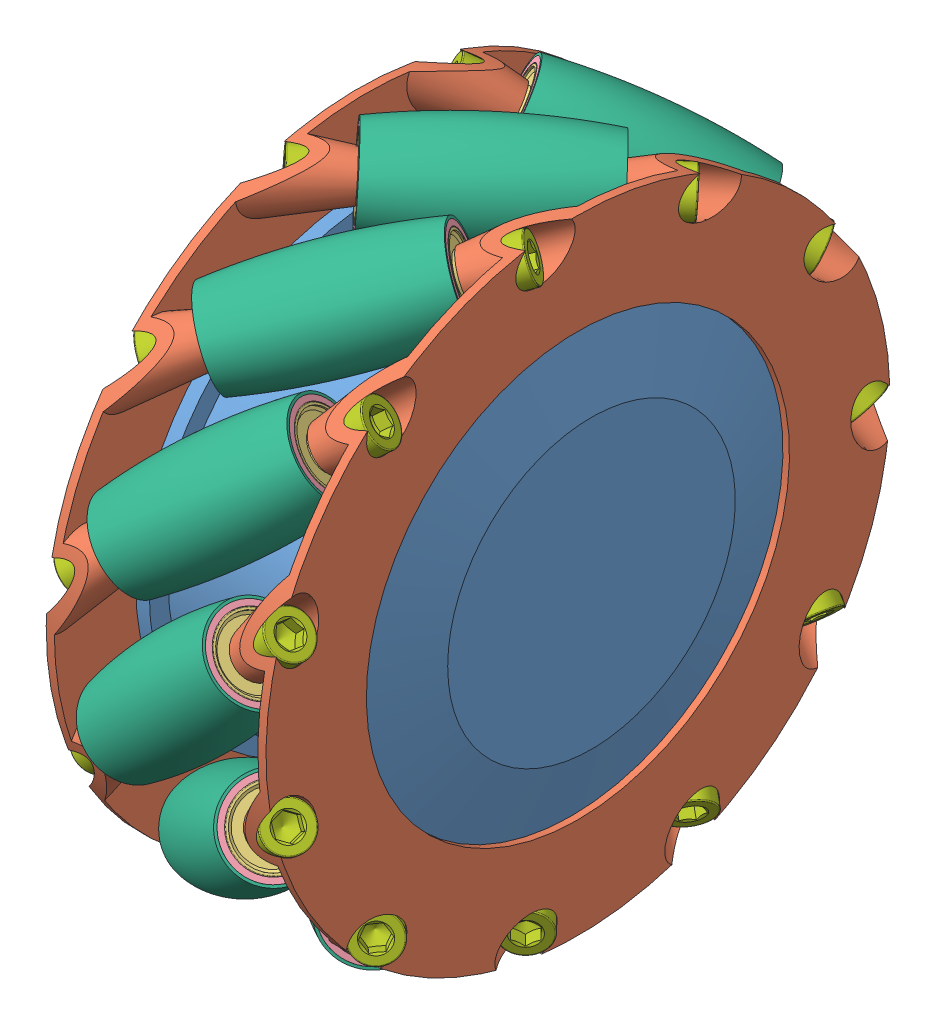
SolidWorks assembly ТП.SH21(К4).01.00 - Колесо Б, configuration 00. Lengths in mm.
Overall size (149.42 275.46 275.46).
102 component instances, 8 part files, 10 mates.
Components (placement in the parent):
- Мотор-колесо ZLLG80ASM800 (мотор)-1: Мотор-колесо ZLLG80ASM800 (мотор) [1 крепление] at origin size (133 170 170)
- ТП.SH21(К4).01.01 - Фланец колеса-1: ТП.SH21(К4).01.01 - Фланец колеса [11] at (-43.5 0 0) x (0 -0.998143 -0.060917) z (-1 0 0) size (230 230 42.83)
- ТП.SH21(К4).01.02.00 - Ролик диагональный-1: ТП.SH21(К4).01.02.00 - Ролик диагональный [00] at (0 101.1602 -8.298) x (0.7067 0.023978 0.707107) z (-0.707107 0.057808 0.70474) size (37 37 69.98)
  - Боченок габарит-1: Боченок габарит [--] at origin size (37 37 91.92) (hidden)
  - Подшипник 6100-1: Подшипник 6100 [--] at (0 0 30.99) x (0 0 1) z (0.161819 -0.986821 0) size (8 26 26)
  - ТП.SH21(К4).01.02.01 - Ступица-1: ТП.SH21(К4).01.02.01 - Ступица [--] at origin size (30 30 69.98)
  - ТП.SH21(К4).01.02.02 - Ось-1: ТП.SH21(К4).01.02.02 - Ось [--] at origin size (14 14 53.98)
  - Подшипник 6100-2: Подшипник 6100 [--] at (0 0 -30.99) x (0 0 -1) z (-0.273874 0.961766 0) size (8 26 26)
  - ТП.SH21(К4).01.02.03 - Покрышка-1: ТП.SH21(К4).01.02.03 - Покрышка [--] at origin size (37 37 69.98)
- ТП.SH21(К4).01.01 - Фланец колеса-2: ТП.SH21(К4).01.01 - Фланец колеса [11] at (43.5 0 0) x (0 -0.974873 0.22276) z (1 0 0) size (230 230 42.83)
- Винты с цилиндрической головкой (ГОСТ 11738-84)-1: Винты с цилиндрической головкой (ГОСТ 11738-84) [Винт М10-(6g)x35 ГОСТ 11738-84] at (-31.1056 103.7032 22.7036) x (0.312231 0.919754 0.237834) z (-0.707107 0.057808 0.70474) size (16 16 45.28)
- Винты с цилиндрической головкой (ГОСТ 11738-84)-2: Винты с цилиндрической головкой (ГОСТ 11738-84) [Винт М10-(6g)x35 ГОСТ 11738-84] at (31.1056 98.6173 -39.2995) x (0.69696 0.225211 0.680828) z (0.707107 -0.057808 -0.70474) size (16 16 45.28)
- Винты с цилиндрической головкой (ГОСТ 11738-84)-4: Винты с цилиндрической головкой (ГОСТ 11738-84) [Винт М10-(6g)x35 ГОСТ 11738-84] at (-31.1056 99.5152 -36.9667) x (0.312231 0.902329 -0.297178) z (-0.707107 0.429643 0.561611) size (16 16 45.28)
- Винты с цилиндрической головкой (ГОСТ 11738-84)-5: Винты с цилиндрической головкой (ГОСТ 11738-84) [Винт М10-(6g)x35 ГОСТ 11738-84] at (-31.1056 63.7318 -84.9004) x (0.312231 0.598421 -0.737838) z (-0.707107 0.665068 0.240175) size (16 16 45.28)
- Винты с цилиндрической головкой (ГОСТ 11738-84)-6: Винты с цилиндрической головкой (ГОСТ 11738-84) [Винт М10-(6g)x35 ГОСТ 11738-84] at (-31.1056 7.714 -105.8787) x (0.312231 0.104518 -0.944239) z (-0.707107 0.68934 -0.157515) size (16 16 45.28)
- Винты с цилиндрической головкой (ГОСТ 11738-84)-7: Винты с цилиндрической головкой (ГОСТ 11738-84) [Винт М10-(6g)x35 ГОСТ 11738-84] at (-31.1056 -50.753 -93.2413) x (0.312231 -0.422568 -0.850852) z (-0.707107 0.49475 -0.505195) size (16 16 45.28)
- Винты с цилиндрической головкой (ГОСТ 11738-84)-8: Винты с цилиндрической головкой (ГОСТ 11738-84) [Винт М10-(6g)x35 ГОСТ 11738-84] at (-31.1056 -93.1062 -51.0005) x (0.312231 -0.815492 -0.487325) z (-0.707107 0.143082 -0.692479) size (16 16 45.28)
- Винты с цилиндрической головкой (ГОСТ 11738-84)-9: Винты с цилиндрической головкой (ГОСТ 11738-84) [Винт М10-(6g)x35 ГОСТ 11738-84] at (-31.1056 -105.8988 7.4327) x (0.312231 -0.949503 0.030925) z (-0.707107 -0.254015 -0.659906) size (16 16 45.28)
- Винты с цилиндрической головкой (ГОСТ 11738-84)-10: Винты с цилиндрической головкой (ГОСТ 11738-84) [Винт М10-(6g)x35 ГОСТ 11738-84] at (-31.1056 -85.0694 63.506) x (0.312231 -0.782054 0.539356) z (-0.707107 -0.570463 -0.417818) size (16 16 45.28)
- Винты с цилиндрической головкой (ГОСТ 11738-84)-11: Винты с цилиндрической головкой (ГОСТ 11738-84) [Винт М10-(6g)x35 ГОСТ 11738-84] at (-31.1056 -37.231 99.4166) x (0.312231 -0.366308 0.876545) z (-0.707107 -0.705794 -0.043075) size (16 16 45.28)
- Винты с цилиндрической головкой (ГОСТ 11738-84)-12: Винты с цилиндрической головкой (ГОСТ 11738-84) [Винт М10-(6g)x35 ГОСТ 11738-84] at (-31.1056 22.428 103.7632) x (0.312231 0.165738 0.935437) z (-0.707107 -0.617039 0.345344) size (16 16 45.28)
- Винты с цилиндрической головкой (ГОСТ 11738-84)-13: Винты с цилиндрической головкой (ГОСТ 11738-84) [Винт М10-(6g)x35 ГОСТ 11738-84] at (-31.1056 74.9662 75.1656) x (0.312231 0.645163 0.697335) z (-0.707107 -0.33238 0.624118) size (16 16 45.28)
- ТП.SH21(К4).01.02.00 - Ролик диагональный-2: ТП.SH21(К4).01.02.00 - Ролик диагональный [00] at (0 80.6152 -61.672) x (0.7067 0.402463 0.581892) z (-0.707107 0.429643 0.561611) size (37 37 69.98)
  - Боченок габарит-1: Боченок габарит [--] at origin size (37 37 91.92) (hidden)
  - Подшипник 6100-1: Подшипник 6100 [--] at (0 0 30.99) x (0 0 1) z (0.161819 -0.986821 0) size (8 26 26)
  - ТП.SH21(К4).01.02.01 - Ступица-1: ТП.SH21(К4).01.02.01 - Ступица [--] at origin size (30 30 69.98)
  - ТП.SH21(К4).01.02.02 - Ось-1: ТП.SH21(К4).01.02.02 - Ось [--] at origin size (14 14 53.98)
  - Подшипник 6100-2: Подшипник 6100 [--] at (0 0 -30.99) x (0 0 -1) z (-0.273874 0.961766 0) size (8 26 26)
  - ТП.SH21(К4).01.02.03 - Покрышка-1: ТП.SH21(К4).01.02.03 - Покрышка [--] at origin size (37 37 69.98)
- ТП.SH21(К4).01.02.00 - Ролик диагональный-3: ТП.SH21(К4).01.02.00 - Ролик диагональный [00] at (0 34.4754 -95.4657) x (0.7067 0.653168 0.271931) z (-0.707107 0.665068 0.240175) size (37 37 69.98)
  - Боченок габарит-1: Боченок габарит [--] at origin size (37 37 91.92) (hidden)
  - Подшипник 6100-1: Подшипник 6100 [--] at (0 0 30.99) x (0 0 1) z (0.161819 -0.986821 0) size (8 26 26)
  - ТП.SH21(К4).01.02.01 - Ступица-1: ТП.SH21(К4).01.02.01 - Ступица [--] at origin size (30 30 69.98)
  - ТП.SH21(К4).01.02.02 - Ось-1: ТП.SH21(К4).01.02.02 - Ось [--] at origin size (14 14 53.98)
  - Подшипник 6100-2: Подшипник 6100 [--] at (0 0 -30.99) x (0 0 -1) z (-0.273874 0.961766 0) size (8 26 26)
  - ТП.SH21(К4).01.02.03 - Покрышка-1: ТП.SH21(К4).01.02.03 - Покрышка [--] at origin size (37 37 69.98)
- ТП.SH21(К4).01.02.00 - Ролик диагональный-4: ТП.SH21(К4).01.02.00 - Ролик диагональный [00] at (0 -22.6101 -98.9497) x (0.7067 0.696497 -0.124366) z (-0.707107 0.68934 -0.157515) size (37 37 69.98)
  - Боченок габарит-1: Боченок габарит [--] at origin size (37 37 91.92) (hidden)
  - Подшипник 6100-1: Подшипник 6100 [--] at (0 0 30.99) x (0 0 1) z (0.161819 -0.986821 0) size (8 26 26)
  - ТП.SH21(К4).01.02.01 - Ступица-1: ТП.SH21(К4).01.02.01 - Ступица [--] at origin size (30 30 69.98)
  - ТП.SH21(К4).01.02.02 - Ось-1: ТП.SH21(К4).01.02.02 - Ось [--] at origin size (14 14 53.98)
  - Подшипник 6100-2: Подшипник 6100 [--] at (0 0 -30.99) x (0 0 -1) z (-0.273874 0.961766 0) size (8 26 26)
  - ТП.SH21(К4).01.02.03 - Покрышка-1: ТП.SH21(К4).01.02.03 - Покрышка [--] at origin size (37 37 69.98)
- ТП.SH21(К4).01.02.00 - Ролик диагональный-5: ТП.SH21(К4).01.02.00 - Ролик диагональный [00] at (0 -72.517 -71.0178) x (0.7067 0.518693 -0.481178) z (-0.707107 0.49475 -0.505195) size (37 37 69.98)
  - Боченок габарит-1: Боченок габарит [--] at origin size (37 37 91.92) (hidden)
  - Подшипник 6100-1: Подшипник 6100 [--] at (0 0 30.99) x (0 0 1) z (0.161819 -0.986821 0) size (8 26 26)
  - ТП.SH21(К4).01.02.01 - Ступица-1: ТП.SH21(К4).01.02.01 - Ступица [--] at origin size (30 30 69.98)
  - ТП.SH21(К4).01.02.02 - Ось-1: ТП.SH21(К4).01.02.02 - Ось [--] at origin size (14 14 53.98)
  - Подшипник 6100-2: Подшипник 6100 [--] at (0 0 -30.99) x (0 0 -1) z (-0.273874 0.961766 0) size (8 26 26)
  - ТП.SH21(К4).01.02.03 - Покрышка-1: ТП.SH21(К4).01.02.03 - Покрышка [--] at origin size (37 37 69.98)
- ТП.SH21(К4).01.02.00 - Ролик диагональный-6: ТП.SH21(К4).01.02.00 - Ролик диагональный [00] at (0 -99.4003 -20.5383) x (0.7067 0.176208 -0.685219) z (-0.707107 0.143082 -0.692479) size (37 37 69.98)
  - Боченок габарит-1: Боченок габарит [--] at origin size (37 37 91.92) (hidden)
  - Подшипник 6100-1: Подшипник 6100 [--] at (0 0 30.99) x (0 0 1) z (0.161819 -0.986821 0) size (8 26 26)
  - ТП.SH21(К4).01.02.01 - Ступица-1: ТП.SH21(К4).01.02.01 - Ступица [--] at origin size (30 30 69.98)
  - ТП.SH21(К4).01.02.02 - Ось-1: ТП.SH21(К4).01.02.02 - Ось [--] at origin size (14 14 53.98)
  - Подшипник 6100-2: Подшипник 6100 [--] at (0 0 -30.99) x (0 0 -1) z (-0.273874 0.961766 0) size (8 26 26)
  - ТП.SH21(К4).01.02.03 - Покрышка-1: ТП.SH21(К4).01.02.03 - Покрышка [--] at origin size (37 37 69.98)
- ТП.SH21(К4).01.02.00 - Ролик диагональный-7: ТП.SH21(К4).01.02.00 - Ролик диагональный [00] at (0 -94.7247 36.462) x (0.7067 -0.222222 -0.671709) z (-0.707107 -0.254015 -0.659906) size (37 37 69.98)
  - Боченок габарит-1: Боченок габарит [--] at origin size (37 37 91.92) (hidden)
  - Подшипник 6100-1: Подшипник 6100 [--] at (0 0 30.99) x (0 0 1) z (0.161819 -0.986821 0) size (8 26 26)
  - ТП.SH21(К4).01.02.01 - Ступица-1: ТП.SH21(К4).01.02.01 - Ступица [--] at origin size (30 30 69.98)
  - ТП.SH21(К4).01.02.02 - Ось-1: ТП.SH21(К4).01.02.02 - Ось [--] at origin size (14 14 53.98)
  - Подшипник 6100-2: Подшипник 6100 [--] at (0 0 -30.99) x (0 0 -1) z (-0.273874 0.961766 0) size (8 26 26)
  - ТП.SH21(К4).01.02.03 - Покрышка-1: ТП.SH21(К4).01.02.03 - Покрышка [--] at origin size (37 37 69.98)
- ТП.SH21(К4).01.02.00 - Ролик диагональный-8: ТП.SH21(К4).01.02.00 - Ролик диагональный [00] at (0 -59.9747 81.8858) x (0.7067 -0.550098 -0.444935) z (-0.707107 -0.570463 -0.417818) size (37 37 69.98)
  - Боченок габарит-1: Боченок габарит [--] at origin size (37 37 91.92) (hidden)
  - Подшипник 6100-1: Подшипник 6100 [--] at (0 0 30.99) x (0 0 1) z (0.161819 -0.986821 0) size (8 26 26)
  - ТП.SH21(К4).01.02.01 - Ступица-1: ТП.SH21(К4).01.02.01 - Ступица [--] at origin size (30 30 69.98)
  - ТП.SH21(К4).01.02.02 - Ось-1: ТП.SH21(К4).01.02.02 - Ось [--] at origin size (14 14 53.98)
  - Подшипник 6100-2: Подшипник 6100 [--] at (0 0 -30.99) x (0 0 -1) z (-0.273874 0.961766 0) size (8 26 26)
  - ТП.SH21(К4).01.02.03 - Покрышка-1: ТП.SH21(К4).01.02.03 - Покрышка [--] at origin size (37 37 69.98)
- ТП.SH21(К4).01.02.00 - Ролик диагональный-9: ТП.SH21(К4).01.02.00 - Ролик диагональный [00] at (0 -6.1831 101.3115) x (0.7067 -0.703322 -0.076898) z (-0.707107 -0.705794 -0.043075) size (37 37 69.98)
  - Боченок габарит-1: Боченок габарит [--] at origin size (37 37 91.92) (hidden)
  - Подшипник 6100-1: Подшипник 6100 [--] at (0 0 30.99) x (0 0 1) z (0.161819 -0.986821 0) size (8 26 26)
  - ТП.SH21(К4).01.02.01 - Ступица-1: ТП.SH21(К4).01.02.01 - Ступица [--] at origin size (30 30 69.98)
  - ТП.SH21(К4).01.02.02 - Ось-1: ТП.SH21(К4).01.02.02 - Ось [--] at origin size (14 14 53.98)
  - Подшипник 6100-2: Подшипник 6100 [--] at (0 0 -30.99) x (0 0 -1) z (-0.273874 0.961766 0) size (8 26 26)
  - ТП.SH21(К4).01.02.03 - Покрышка-1: ТП.SH21(К4).01.02.03 - Покрышка [--] at origin size (37 37 69.98)
- ТП.SH21(К4).01.02.00 - Ролик диагональный-10: ТП.SH21(К4).01.02.00 - Ролик диагональный [00] at (0 49.5716 88.5715) x (0.7067 -0.633246 0.315554) z (-0.707107 -0.617039 0.345344) size (37 37 69.98)
  - Боченок габарит-1: Боченок габарит [--] at origin size (37 37 91.92) (hidden)
  - Подшипник 6100-1: Подшипник 6100 [--] at (0 0 30.99) x (0 0 1) z (0.161819 -0.986821 0) size (8 26 26)
  - ТП.SH21(К4).01.02.01 - Ступица-1: ТП.SH21(К4).01.02.01 - Ступица [--] at origin size (30 30 69.98)
  - ТП.SH21(К4).01.02.02 - Ось-1: ТП.SH21(К4).01.02.02 - Ось [--] at origin size (14 14 53.98)
  - Подшипник 6100-2: Подшипник 6100 [--] at (0 0 -30.99) x (0 0 -1) z (-0.273874 0.961766 0) size (8 26 26)
  - ТП.SH21(К4).01.02.03 - Покрышка-1: ТП.SH21(К4).01.02.03 - Покрышка [--] at origin size (37 37 69.98)
- ТП.SH21(К4).01.02.00 - Ролик диагональный-11: ТП.SH21(К4).01.02.00 - Ролик диагональный [00] at (0 89.5876 47.7107) x (0.7067 -0.362119 0.60782) z (-0.707107 -0.33238 0.624118) size (37 37 69.98)
  - Боченок габарит-1: Боченок габарит [--] at origin size (37 37 91.92) (hidden)
  - Подшипник 6100-1: Подшипник 6100 [--] at (0 0 30.99) x (0 0 1) z (0.161819 -0.986821 0) size (8 26 26)
  - ТП.SH21(К4).01.02.01 - Ступица-1: ТП.SH21(К4).01.02.01 - Ступица [--] at origin size (30 30 69.98)
  - ТП.SH21(К4).01.02.02 - Ось-1: ТП.SH21(К4).01.02.02 - Ось [--] at origin size (14 14 53.98)
  - Подшипник 6100-2: Подшипник 6100 [--] at (0 0 -30.99) x (0 0 -1) z (-0.273874 0.961766 0) size (8 26 26)
  - ТП.SH21(К4).01.02.03 - Покрышка-1: ТП.SH21(К4).01.02.03 - Покрышка [--] at origin size (37 37 69.98)
- Винты с цилиндрической головкой (ГОСТ 11738-84)-14: Винты с цилиндрической головкой (ГОСТ 11738-84) [Винт М10-(6g)x35 ГОСТ 11738-84] at (31.1056 61.7152 -86.3773) x (0.69696 0.557543 0.45099) z (0.707107 -0.429643 -0.561611) size (16 16 45.28)
- Винты с цилиндрической головкой (ГОСТ 11738-84)-15: Винты с цилиндрической головкой (ГОСТ 11738-84) [Винт М10-(6g)x35 ГОСТ 11738-84] at (31.1056 5.219 -106.031) x (0.69696 0.712859 0.077966) z (0.707107 -0.665068 -0.240175) size (16 16 45.28)
- Винты с цилиндрической головкой (ГОСТ 11738-84)-16: Винты с цилиндрической головкой (ГОСТ 11738-84) [Винт М10-(6g)x35 ГОСТ 11738-84] at (31.1056 -52.9342 -92.0206) x (0.69696 0.641847 -0.319811) z (0.707107 -0.68934 0.157515) size (16 16 45.28)
- Винты с цилиндрической головкой (ГОСТ 11738-84)-17: Винты с цилиндрической головкой (ГОСТ 11738-84) [Винт М10-(6g)x35 ГОСТ 11738-84] at (31.1056 -94.2811 -48.7943) x (0.69696 0.367053 -0.616051) z (0.707107 -0.49475 0.505195) size (16 16 45.28)
- Винты с цилиндрической головкой (ГОСТ 11738-84)-18: Винты с цилиндрической головкой (ГОСТ 11738-84) [Винт М10-(6g)x35 ГОСТ 11738-84] at (31.1056 -105.6945 9.9239) x (0.69696 -0.024278 -0.716699) z (0.707107 -0.143082 0.692479) size (16 16 45.28)
- Винты с цилиндрической головкой (ГОСТ 11738-84)-19: Винты с цилиндрической головкой (ГОСТ 11738-84) [Винт М10-(6g)x35 ГОСТ 11738-84] at (31.1056 -83.5506 65.4913) x (0.69696 -0.4079 -0.5898) z (0.707107 0.254015 0.659906) size (16 16 45.28)
- Винты с цилиндрической головкой (ГОСТ 11738-84)-20: Винты с цилиндрической головкой (ГОСТ 11738-84) [Винт М10-(6g)x35 ГОСТ 11738-84] at (31.1056 -34.88 100.2656) x (0.69696 -0.662017 -0.275644) z (0.707107 0.570463 0.417818) size (16 16 45.28)
- Винты с цилиндрической головкой (ГОСТ 11738-84)-21: Винты с цилиндрической головкой (ГОСТ 11738-84) [Винт М10-(6g)x35 ГОСТ 11738-84] at (31.1056 24.8648 103.2064) x (0.69696 -0.705949 0.126027) z (0.707107 0.705794 0.043075) size (16 16 45.28)
- Винты с цилиндрической головкой (ГОСТ 11738-84)-22: Винты с цилиндрической головкой (ГОСТ 11738-84) [Винт М10-(6g)x35 ГОСТ 11738-84] at (31.1056 76.7151 73.3798) x (0.69696 -0.525746 0.487686) z (0.707107 0.617039 -0.345344) size (16 16 45.28)
- Винты с цилиндрической головкой (ГОСТ 11738-84)-23: Винты с цилиндрической головкой (ГОСТ 11738-84) [Винт М10-(6g)x35 ГОСТ 11738-84] at (31.1056 104.209 20.2557) x (0.69696 -0.178623 0.694507) z (0.707107 0.33238 -0.624118) size (16 16 45.28)
Mates (geometry in assembly coordinates):
- Совпадение1: coincident: plane of Мотор-колесо ZLLG80ASM800 (мотор)-1 through (-37.5 85 0) normal (-1 0 0); plane of ТП.SH21(К4).01.01 - Фланец колеса-1 through (-37.5 0 0) normal (1 0 0)
- Концентричный1: concentric: circle of Мотор-колесо ZLLG80ASM800 (мотор)-1; cylinder of ТП.SH21(К4).01.01 - Фланец колеса-1 through (-40.5 0 0) axis (1 0 0) radius 78
- Концентричный2: concentric: cylinder of ТП.SH21(К4).01.01 - Фланец колеса-1 through (-6.3569 101.6799 -1.9623) axis (0.707107 -0.057808 -0.70474) radius 5; cylinder of ТП.SH21(К4).01.02.00 - Ролик диагональный-1/Подшипник 6100-2 through (-685.1935 157.177 674.602) axis (-0.707107 0.057808 0.70474) radius 5
- Совпадение2: coincident: plane of ТП.SH21(К4).01.01 - Фланец колеса-1 through (-24.7417 103.183 16.3609) normal (0.707107 -0.057808 -0.70474); plane of ТП.SH21(К4).01.02.00 - Ролик диагональный-1/Подшипник 6100-1 through (-28.9493 102.072 12.2303) normal (-0.707107 0.057808 0.70474)
- Концентричный3: concentric: cylinder of ТП.SH21(К4).01.02.00 - Ролик диагональный-1/Подшипник 6100-2 through (-685.1935 157.177 674.602) axis (-0.707107 0.057808 0.70474) radius 5; cylinder of ТП.SH21(К4).01.01 - Фланец колеса-2 through (6.3569 100.6405 -14.6336) axis (-0.707107 0.057808 0.70474) radius 5
- Совпадение3: coincident: plane of Мотор-колесо ZLLG80ASM800 (мотор)-1 through (37.5 85 0) normal (1 0 0); plane of ТП.SH21(К4).01.01 - Фланец колеса-2 through (37.5 0 0) normal (-1 0 0)
- Концентричный4: concentric: cylinder of ТП.SH21(К4).01.01 - Фланец колеса-1 through (-6.3569 101.6799 -1.9623) axis (0.707107 -0.057808 -0.70474) radius 5; cylinder of Винты с цилиндрической головкой (ГОСТ 11738-84)-1 through (-6.3569 101.6799 -1.9623) axis (0.707107 -0.057808 -0.70474) radius 5
- Совпадение4: coincident: plane of ТП.SH21(К4).01.01 - Фланец колеса-1 through (-31.1056 103.7032 22.7036) normal (-0.707107 0.057808 0.70474); plane of Винты с цилиндрической головкой (ГОСТ 11738-84)-1 through (-34.6585 105.8772 18.9604) normal (0.707107 -0.057808 -0.70474)
- Концентричный5: concentric: cylinder of ТП.SH21(К4).01.01 - Фланец колеса-2 through (6.3569 100.6405 -14.6336) axis (-0.707107 0.057808 0.70474) radius 5; cylinder of Винты с цилиндрической головкой (ГОСТ 11738-84)-2 through (6.3569 100.6405 -14.6336) axis (-0.707107 0.057808 0.70474) radius 5
- Совпадение5: coincident: plane of ТП.SH21(К4).01.01 - Фланец колеса-2 through (31.1056 98.6173 -39.2995) normal (0.707107 -0.057808 -0.70474); plane of Винты с цилиндрической головкой (ГОСТ 11738-84)-2 through (31.774 93.1707 -38.1821) normal (-0.707107 0.057808 0.70474)
